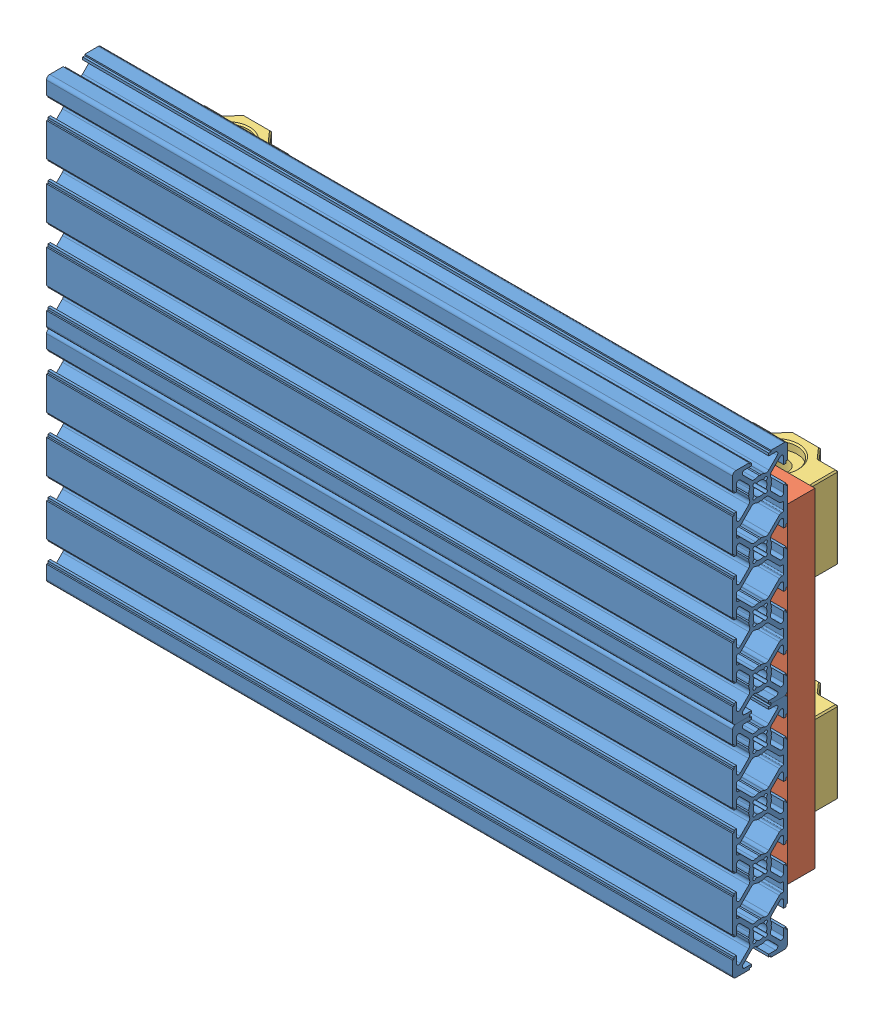
SolidWorks assembly AXIS_Y_DYNAMIC-but_bigger, configuration Default. Lengths in mm.
Overall size (250 160 52.8).
24 component instances, 7 part files, 33 mates.
Components (placement in the parent):
- 20x80x250_surface-1: 20x80x250_surface [Varsayılan] at (125 -70 0) x (0 1 0) z (1 0 0) size (80 20 250)
- 20x80x250_surface-2: 20x80x250_surface [Varsayılan] at (125 10 0) x (0 1 0) z (1 0 0) size (80 20 250)
- y_axis_elevation-1: y_axis_elevation [Default] at (100 0 -20) x (0 1 0) z (1 0 0) size (120 10 50)
- y_axis_elevation-3: y_axis_elevation [Default] at (-100 0 -20) x (0 1 0) z (1 0 0) size (120 10 50)
- linear_bearing_caged-5: linear_bearing_caged [Default] at (100 37 -31) x (1 0 0) z (0 1 0) size (34 22 30)
- linear_bearing_caged-6: linear_bearing_caged [Default] at (100 -37 -31) x (1 0 0) z (0 1 0) size (34 22 30)
- linear_bearing_caged-7: linear_bearing_caged [Default] at (-100 37 -31) x (1 0 0) z (0 1 0) size (34 22 30)
- linear_bearing_caged-8: linear_bearing_caged [Default] at (-100 -37 -31) x (1 0 0) z (0 1 0) size (34 22 30)
- SK10_rod_holder-1: SK10_rod_holder [Default] at (0 3 -30) x (1 0 0) z (0 1 0) size (42 32.8 14)
- trapezoidal_nut-1: trapezoidal_nut [Default] at (0 21 -30) x (0.995058 0 0.099296) z (0 -1 0) size (22 22 15)
- socket csink head cap screw 10642_din-1: socket csink head cap screw 10642_din [EN ISO 10642 - M5 x 16 - 16N] at (100 50 -19.865) x (0 0 1) z (-0.999963 -0.008553 0) size (16 9.43 9.43)
- socket csink head cap screw 10642_din-2: socket csink head cap screw 10642_din [EN ISO 10642 - M5 x 16 - 16N] at (100 30 -19.865) x (0 0 1) z (-0.999768 -0.021532 0) size (16 9.43 9.43)
- socket csink head cap screw 10642_din-3: socket csink head cap screw 10642_din [EN ISO 10642 - M5 x 16 - 16N] at (100 10 -19.865) x (0 0 1) z (-0.99983 -0.018451 0) size (16 9.43 9.43)
- socket csink head cap screw 10642_din-4: socket csink head cap screw 10642_din [EN ISO 10642 - M5 x 16 - 16N] at (100 -10 -19.865) x (0 0 1) z (-0.999886 -0.015083 0) size (16 9.43 9.43)
- socket csink head cap screw 10642_din-5: socket csink head cap screw 10642_din [EN ISO 10642 - M5 x 16 - 16N] at (100 -30 -19.865) x (0 0 1) z (-0.99994 -0.010952 0) size (16 9.43 9.43)
- socket csink head cap screw 10642_din-6: socket csink head cap screw 10642_din [EN ISO 10642 - M5 x 16 - 16N] at (-100 50 -19.865) x (0 0 1) z (-0.999886 0.015089 0) size (16 9.43 9.43)
- socket csink head cap screw 10642_din-7: socket csink head cap screw 10642_din [EN ISO 10642 - M5 x 16 - 16N] at (-100 30 -19.865) x (0 0 1) z (-1 0.000244 0) size (16 9.43 9.43)
- socket csink head cap screw 10642_din-8: socket csink head cap screw 10642_din [EN ISO 10642 - M5 x 16 - 16N] at (-100 10 -19.865) x (0 0 1) z (-1 -0.000391 0) size (16 9.43 9.43)
- socket csink head cap screw 10642_din-9: socket csink head cap screw 10642_din [EN ISO 10642 - M5 x 16 - 16N] at (-100 -10 -19.865) x (0 0 1) z (-0.999973 0.007303 0) size (16 9.43 9.43)
- socket csink head cap screw 10642_din-10: socket csink head cap screw 10642_din [EN ISO 10642 - M5 x 16 - 16N] at (-100 -30 -19.865) x (0 0 1) z (-0.999988 0.004919 0) size (16 9.43 9.43)
- socket csink head cap screw 10642_din-11: socket csink head cap screw 10642_din [EN ISO 10642 - M5 x 16 - 16N] at (-100 -50 -19.865) x (0 0 1) z (-0.999959 0.009039 0) size (16 9.43 9.43)
- socket csink head cap screw 10642_din-12: socket csink head cap screw 10642_din [EN ISO 10642 - M5 x 16 - 16N] at (100 -50 -19.865) x (0 0 1) z (-0.999985 -0.005519 0) size (16 9.43 9.43)
- socket head cap screw 4762_din-2: socket head cap screw 4762_din [EN ISO 4762 M5 x 10 - 10N] at (16 10 -21) x (0 0 1) z (-1 0 0) size (15 8.5 8.5)
- socket head cap screw 4762_din-3: socket head cap screw 4762_din [EN ISO 4762 M5 x 10 - 10N] at (-16 10 -21) x (0 0 1) z (-1 0 0) size (15 8.5 8.5)
Mates (geometry in assembly coordinates):
- Coincident1: coincident anti-aligned: plane of 20x80x250_surface-1 through (-125 0 3.95) normal (0 1 0); plane of 20x80x250_surface-2 through (-125 0 8.8) normal (0 -1 0)
- Coincident2: coincident aligned: plane of 20x80x250_surface-1 through (-125 -13.95 10) normal (0 0 1); plane of 20x80x250_surface-2 through (-125 26.05 10) normal (0 0 1)
- Coincident3: coincident aligned: plane of 20x80x250_surface-1 through (125 -75.6787 -7.8) normal (1 0 0); plane of 20x80x250_surface-2 through (125 4.3213 -7.8) normal (1 0 0)
- Coincident4: coincident anti-aligned: plane of 20x80x250_surface-2 through (-125 53.95 -10) normal (0 0 -1); plane of y_axis_elevation-1 through (100 0 -10) normal (0 0 1)
- Coincident5: coincident aligned: plane of 20x80x250_surface-2 through (125 4.3213 -7.8) normal (1 0 0); plane of y_axis_elevation-1 through (125 60 -10) normal (1 0 0)
- Width1: width anti-aligned: plane of y_axis_elevation-1 through (125 60 -10) normal (0 1 0); plane of 20x80x250_surface-1 through (125 -60 -10) normal (0 -1 0); plane of y_axis_elevation-1 through (-125 -80 8.8) normal (0 -1 0); plane of 20x80x250_surface-2 through (-125 80 3.95) normal (0 1 0)
- Coincident6: coincident anti-aligned: plane of 20x80x250_surface-2 through (-125 53.95 -10) normal (0 0 -1); plane of y_axis_elevation-3 through (-100 0 -10) normal (0 0 1)
- Coincident7: coincident aligned: plane of 20x80x250_surface-2 through (-125 4.3213 -7.8) normal (-1 0 0); plane of y_axis_elevation-3 through (-125 60 -10) normal (-1 0 0)
- Coincident8: coincident aligned: plane of y_axis_elevation-1 through (125 60 -10) normal (0 1 0); plane of y_axis_elevation-3 through (-75 60 -10) normal (0 1 0)
- Coincident9: coincident anti-aligned: plane of y_axis_elevation-1 through (100 0 -20) normal (0 0 -1); plane of linear_bearing_caged-5 through (117 52 -20) normal (0 0 1)
- Concentric1: concentric anti-aligned: cylinder of y_axis_elevation-1 through (112 46 -20) axis (0 0 1) radius 1.5; cylinder of linear_bearing_caged-5 through (112 46 -15.7574) axis (0 0 -1) radius 1.5
- Concentric2: concentric anti-aligned: cylinder of y_axis_elevation-1 through (88 28 -20) axis (0 0 1) radius 1.5; cylinder of linear_bearing_caged-5 through (88 28 -15.7574) axis (0 0 -1) radius 1.5
- Coincident38: coincident anti-aligned: plane of SK10_rod_holder-1 through (0 17 -30) normal (0 1 0); plane of trapezoidal_nut-1 through (0 17 -30) normal (0 -1 0)
- Concentric31: concentric anti-aligned: cylinder of SK10_rod_holder-1 through (0 17 -30) axis (0 -1 0) radius 5; cylinder of trapezoidal_nut-1 through (0 6 -30) axis (0 1 0) radius 5.15
- Coincident40: coincident anti-aligned: plane of 20x80x250_surface-2 through (-125 13.95 -10) normal (0 0 -1); plane of SK10_rod_holder-1 through (-21 17 -10) normal (0 0 1)
- Width2: width aligned: plane of SK10_rod_holder-1 through (0 17 -30) normal (0 1 0); plane of 20x80x250_surface-2 through (0 3 -30) normal (0 -1 0); plane of SK10_rod_holder-1 through (-125 13.1768 -4.1667) normal (0 -0.707107 -0.707107); plane of 20x80x250_surface-2 through (-125 3.7556 -7.2343) normal (0 0.707107 -0.707107)
- Width3: width anti-aligned: plane of SK10_rod_holder-1 through (-9 17 -42.8) normal (-1 0 0); plane of y_axis_elevation-3 through (9 17 -42.8) normal (1 0 0); plane of SK10_rod_holder-1 through (-75 60 -10) normal (1 0 0); plane of y_axis_elevation-1 through (75 60 -10) normal (-1 0 0)
- Coincident41: coincident aligned: cone of y_axis_elevation-1 through (100 50 -20) axis (0 0 1); cone of socket csink head cap screw 10642_din-1 through (100 50 -18.98) axis (0 0 1)
- Coincident42: coincident aligned: cone of y_axis_elevation-1 through (100 30 -20) axis (0 0 1); cone of socket csink head cap screw 10642_din-2 through (100 30 -18.98) axis (0 0 1)
- Coincident43: coincident aligned: cone of y_axis_elevation-1 through (100 10 -20) axis (0 0 1); cone of socket csink head cap screw 10642_din-3 through (100 10 -18.98) axis (0 0 1)
- Coincident44: coincident aligned: cone of y_axis_elevation-1 through (100 -10 -20) axis (0 0 1); cone of socket csink head cap screw 10642_din-4 through (100 -10 -18.98) axis (0 0 1)
- Coincident45: coincident aligned: cone of y_axis_elevation-1 through (100 -30 -20) axis (0 0 1); cone of socket csink head cap screw 10642_din-5 through (100 -30 -18.98) axis (0 0 1)
- Coincident46: coincident aligned: cone of y_axis_elevation-3 through (-100 50 -20) axis (0 0 1); cone of socket csink head cap screw 10642_din-6 through (-100 50 -18.98) axis (0 0 1)
- Coincident47: coincident aligned: cone of y_axis_elevation-3 through (-100 30 -20) axis (0 0 1); cone of socket csink head cap screw 10642_din-7 through (-100 30 -18.98) axis (0 0 1)
- Coincident48: coincident aligned: cone of y_axis_elevation-3 through (-100 10 -20) axis (0 0 1); cone of socket csink head cap screw 10642_din-8 through (-100 10 -18.98) axis (0 0 1)
- Coincident49: coincident aligned: cone of y_axis_elevation-3 through (-100 -10 -20) axis (0 0 1); cone of socket csink head cap screw 10642_din-9 through (-100 -10 -18.98) axis (0 0 1)
- Coincident50: coincident aligned: cone of y_axis_elevation-3 through (-100 -30 -20) axis (0 0 1); cone of socket csink head cap screw 10642_din-10 through (-100 -30 -18.98) axis (0 0 1)
- Coincident51: coincident aligned: cone of y_axis_elevation-3 through (-100 -50 -20) axis (0 0 1); cone of socket csink head cap screw 10642_din-11 through (-100 -50 -18.98) axis (0 0 1)
- Coincident52: coincident aligned: cone of y_axis_elevation-1 through (100 -50 -20) axis (0 0 1); cone of socket csink head cap screw 10642_din-12 through (100 -50 -18.98) axis (0 0 1)
- Concentric32: concentric aligned: cylinder of SK10_rod_holder-1 through (16 10 -10) axis (0 0 -1) radius 2.75; cylinder of socket head cap screw 4762_din-2 through (16 10 -52.75) axis (0 0 -1) radius 4.25
- Coincident54: coincident anti-aligned: plane of SK10_rod_holder-1 through (9 17 -16) normal (0 0 -1); plane of socket head cap screw 4762_din-2 through (16 14.25 -16) normal (0 0 1)
- Concentric33: concentric aligned: cylinder of SK10_rod_holder-1 through (-16 10 -10) axis (0 0 -1) radius 2.75; cylinder of socket head cap screw 4762_din-3 through (-16 10 -52.75) axis (0 0 -1) radius 4.25
- Coincident55: coincident anti-aligned: plane of SK10_rod_holder-1 through (-9 17 -16) normal (0 0 -1); plane of socket head cap screw 4762_din-3 through (-16 14.25 -16) normal (0 0 1)
